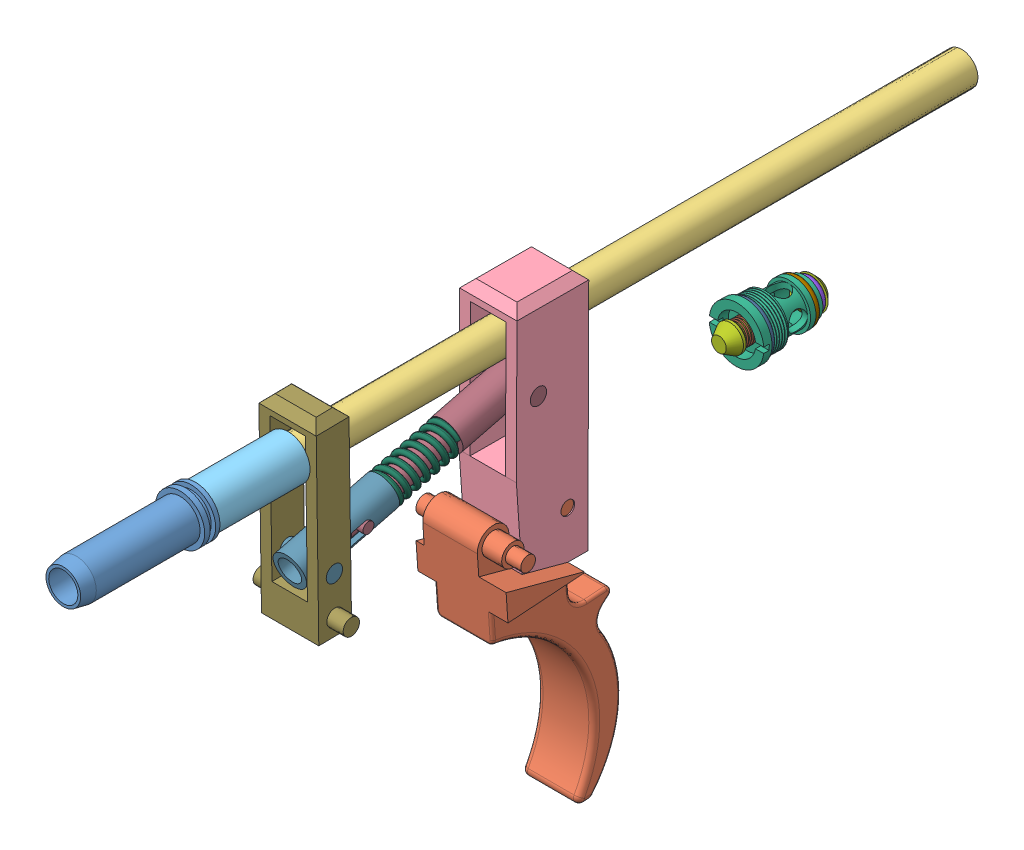
SolidWorks assembly NBB Box Nr1, configuration Standard. Lengths in mm.
Overall size (19 85.68 164.54).
17 component instances, 16 part files, 13 mates.
Components (placement in the parent):
- V3 GB mit allen wichtigen maßen-1: V3 GB mit allen wichtigen maßen [Standard] at (-8.9075 3.8216 0) size (25.5 86.02 179.1) (hidden)
- G36 Nozzle-1: G36 Nozzle [Standard] at (3.8425 21.6759 53.0173) x (0.661488 -0.749956 0) z (0 0 1) size (9 9 24.2)
- G36 Abzug-1: G36 Abzug [Standard] at (-2.9575 -5.257 -50.8307) x (1 0 0) z (0 -0.068721 0.997636) size (19 51.7 22)
- NBB Gasrohr-1: NBB Gasrohr [Standard] at origin size (6 6 155)
- NBB Abzugstrebe-2: NBB Abzugstrebe [Standard] at (0.3 -0.0035 -0.03) x (1 0 0) z (0 0.003935 0.999992) size (10.5 44.39 13.15)
- NBB Gasrohrmantel für Nozzle-1: NBB Gasrohrmantel für Nozzle [Standard] at (-14.9553 10.2193 2.6362) x (0.661488 -0.749956 0) z (0 0 1) size (8 8 17)
- Auslassventil-1: Auslassventil [Standard] at (6.4602 -0.3801 -53.3864) x (1 0 0) z (0 0.999848 -0.017452) size (11.07 18 11.07)
  - Auslassventil_Body-1: Auslassventil_Body [Standard] at (-2.9022 -6.2079 0) size (10.39 12.4 10)
  - Auslassventil_Stift-1: Auslassventil_Stift [Standard] at (-2.9022 -9.4393 0) x (0.560057 0 -0.828454) z (0.828454 0 0.560057) size (6 18 6)
  - ORing1-1: ORing1 [Standard] at (-2.9022 6.8107 0) x (0.890246 0 -0.45548) z (0.45548 0 0.890246) size (6 1.5 6)
  - ORing2-1: ORing2 [Standard] at (-2.9022 4.7921 0) x (0.836929 0 0.547312) z (-0.547312 0 0.836929) size (8 1 8)
  - Oring3-1: Oring3 [Standard] at (-2.9022 -4.2079 0) size (9.5 1 9.5)
  - Feder-1: Feder [Standard] at (-2.9022 -6.7027 0) x (0.967474 0 -0.252969) z (0.252969 0 0.967474) size (4.91 2.75 4.25)
- NBB Nozzlestrebe-1: NBB Nozzlestrebe [Standard] at (43.522 0.3591 0.042) x (1 0 0) z (0 -0.014024 0.999902) size (16.5 35 6)
- NBB Strebenverbindung lang-1: NBB Strebenverbindung lang [Standard] at (16.635 51.756 -20.1652) x (0 0.244965 -0.969532) z (1 0 0) size (35 6 10.5)
- NBB Strebenverbindung kurz-1: NBB Strebenverbindung kurz [Standard] at (16.635 51.756 -20.1652) x (0 0.244965 -0.969532) z (1 0 0) size (17.55 6 10.5)
- NBB Strebenverbindung Feder-1: NBB Strebenverbindung Feder [Standard] at (3.7428 7.6204 17.8312) x (-0.96959 -0.23728 -0.059952) z (0 0.244965 -0.969532) size (6.33 6.1 13.08)
Mates (geometry in assembly coordinates):
- Sperren3: lock: unknown of ?; unknown of ?
- Konzentrisch8: concentric anti-aligned: cylinder of V3 GB mit allen wichtigen maßen-1 through (-13.1575 -7.6241 0.8811) axis (1 0 0) radius 1.6; cylinder of G36 Abzug-1 through (13.4425 -7.6241 0.8811) axis (-1 0 0) radius 1.35
- Abstand2: distance = 0.6 mm aligned: plane of G36 Abzug-1 through (13.4425 -7.6241 0.8811) normal (1 0 0); plane of V3 GB mit allen wichtigen maßen-1 through (12.8425 -47.8241 -93.7189) normal (1 0 0)
- Konzentrisch9: concentric aligned: cylinder of G36 Nozzle-1 through (3.8425 21.6759 85.4931) axis (0 0 1) radius 2.675; cylinder of NBB Gasrohr-1 through (3.8425 21.6759 -88.1189) axis (0 0 1) radius 3
- Sperren6: lock: unknown of ?; unknown of NBB Gasrohr-1
- Konzentrisch14: concentric anti-aligned: cylinder of V3 GB mit allen wichtigen maßen-1 through (-8.9075 -2.8623 31.8601) axis (1 0 0) radius 1.5; cylinder of NBB Nozzlestrebe-1 through (12.0425 -2.8623 31.8601) axis (-1 0 0) radius 1.5
- Abstand5: distance = 0.8 mm aligned: plane of NBB Nozzlestrebe-1 through (12.0425 -2.8623 31.8601) normal (1 0 0); plane of V3 GB mit allen wichtigen maßen-1 through (12.8425 -47.8241 -93.7189) normal (1 0 0)
- Konzentrisch15: concentric anti-aligned: cylinder of NBB Strebenverbindung lang-1 through (3.7925 2.3286 39.1158) axis (0 -0.244965 0.969532) radius 2; cylinder of NBB Strebenverbindung kurz-1 through (3.7925 2.802 37.2422) axis (0 0.244965 -0.969532) radius 2.1
- Abstand6: distance = 12 mm anti-aligned: plane of NBB Strebenverbindung kurz-1 through (-15.365 14.0876 19.4652) normal (0 0.244965 -0.969532); plane of NBB Strebenverbindung lang-1 through (3.7925 12.5799 6.7072) normal (0 -0.244965 0.969532)
- Konzentrisch16: concentric aligned: cylinder of NBB Abzugstrebe-2 through (-1.4575 13.5804 -5.4172) axis (1 0 0) radius 1.5; cylinder of NBB Strebenverbindung lang-1 through (-5.365 13.5804 -5.4172) axis (1 0 0) radius 1.5
- Deckungsgleich20: coincident aligned: plane of NBB Abzugstrebe-2 through (9.0425 -15.4036 -1.3031) normal (1 0 0); plane of NBB Strebenverbindung lang-1 through (9.0425 25.095 -33.4506) normal (1 0 0)
- Konzentrisch17: concentric aligned: cylinder of NBB Nozzlestrebe-1 through (-4.4575 4.137 31.9583) axis (1 0 0) radius 1.5; cylinder of NBB Strebenverbindung kurz-1 through (-15.365 4.137 31.9583) axis (1 0 0) radius 1.5
- Sperren7: lock: unknown of G36 Nozzle-1; unknown of NBB Abzugstrebe-2
